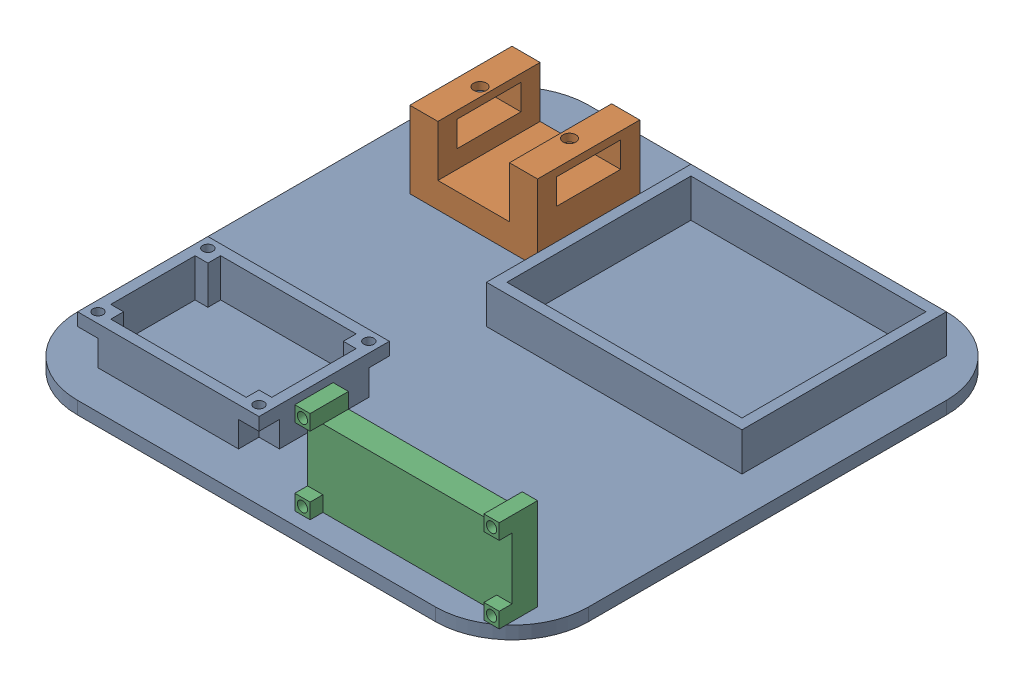
SolidWorks assembly Sun_Tracker, configuration Default. Lengths in mm.
Overall size (200 41 200).
3 component instances, 3 part files, 6 mates.
Components (placement in the parent):
- Base-1: Base [Default] at origin size (200 20 200)
- Step_Motor_Mount-1: Step_Motor_Mount [Default] at (25 5 -135) size (50 30 40)
- LCD_Holder-1: LCD_Holder [Default] at (110 5 -20) size (80 36 15)
Mates (geometry in assembly coordinates):
- Coincident9: coincident anti-aligned: plane of Base-1 through (0 5 0) normal (0 1 0); plane of Step_Motor_Mount-1 through (25 5 -135) normal (0 -1 0)
- Distance1: distance = 25 mm: line of Step_Motor_Mount-1 through (25 5 -175) axis (0 0 1); line of Base-1 through (0 5 -170) axis (0 0 1)
- Distance2: distance = 25 mm: line of Step_Motor_Mount-1 through (75 5 -175) axis (-1 0 0); line of Base-1 through (170 5 -200) axis (-1 0 0)
- Coincident10: coincident anti-aligned: plane of Base-1 through (0 5 0) normal (0 1 0); plane of LCD_Holder-1 through (110 5 -10) normal (0 -1 0)
- Distance3: distance = 10 mm: line of LCD_Holder-1 through (190 5 -5) axis (0 0 -1); line of Base-1 through (200 5 -30) axis (0 0 -1)
- Distance4: distance = 10 mm: line of LCD_Holder-1 through (116 5 -10) axis (1 0 0); line of Base-1 through (30 5 0) axis (1 0 0)
